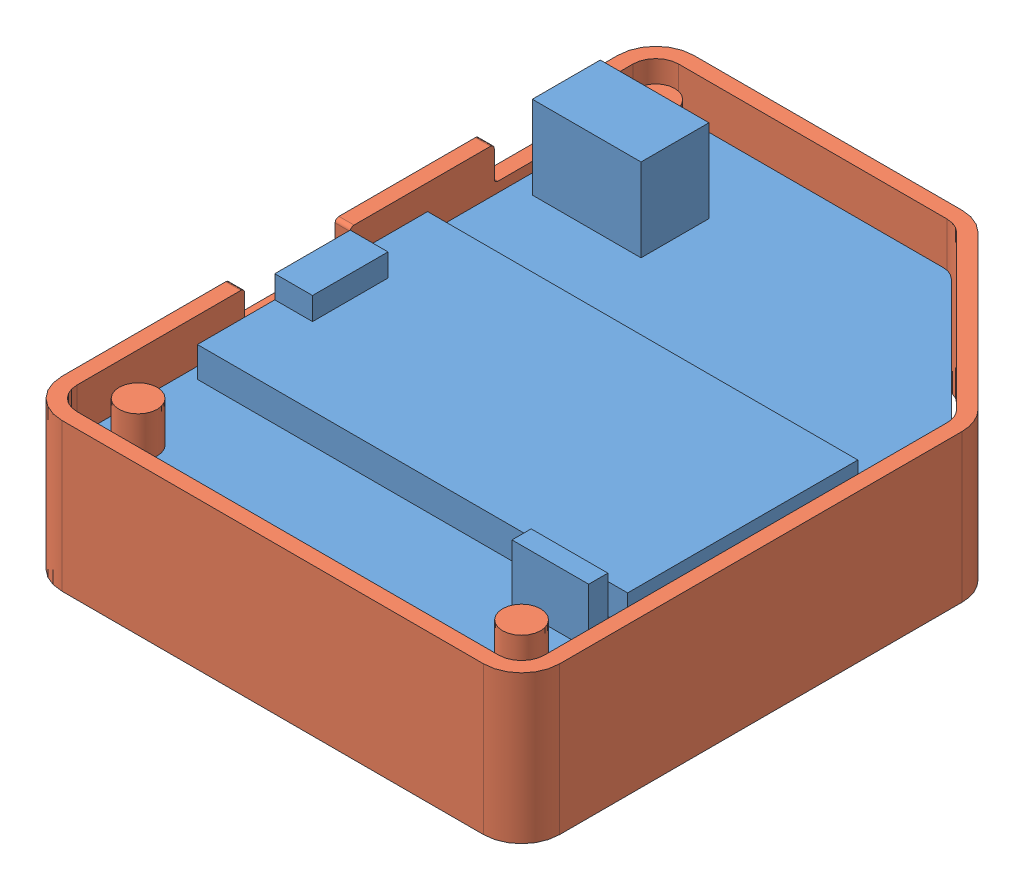
SolidWorks assembly Housing_Assembly, configuration Default. Lengths in mm.
Overall size (65.96 25.27 83.74).
2 component instances, 2 part files, 1 mates.
Components (placement in the parent):
- PCB-1: PCB [Default] at origin size (60.96 21.67 78.74)
- Housing-1: Housing [Default] at origin size (65.96 19.6 83.74)
Mates (geometry in assembly coordinates):
- Coincident3: coordinate: point of PCB-1
